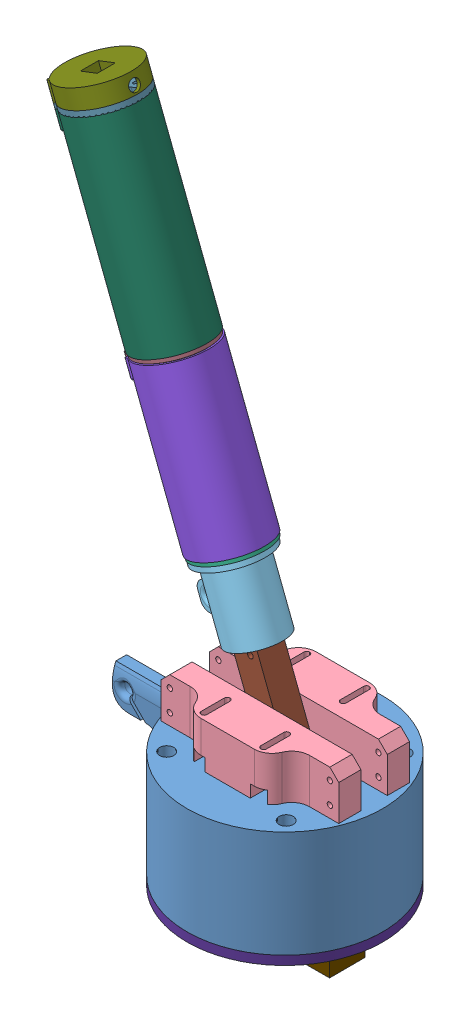
SolidWorks assembly twin_collective, configuration По умолчанию. Lengths in mm.
Overall size (179.32 375.53 110.36).
20 component instances, 18 part files, 53 mates.
Components (placement in the parent):
- twin_collective_enclosure_twin_collective01-1: twin_collective_enclosure_twin_collective01 [По умолчанию] at origin size (147.09 60.09 110)
- twin_collective_lever_frame_twin_collective04-1: twin_collective_lever_frame_twin_collective04 [По умолчанию] at (25.25 42 0) x (0 0 1) z (0 -1 0) size (56 48 30)
- 608_bearing_v1-1: 608_bearing_v1 [По умолчанию] at (9.25 42 10.5) x (1 0 0) z (0 -1 0) size (22 7.15 22)
- 608_bearing_v1-2: 608_bearing_v1 [По умолчанию] at (9.25 42 -10.5) x (1 0 0) z (0 1 0) size (22 7.15 22)
- twin_collective_tensioner_twin_collective06-3: twin_collective_tensioner_twin_collective06 [По умолчанию] at (-0.1 60 19.6) x (0 0 -1) z (1 0 0) size (25 25 100)
- twin_collective_tensioner_twin_collective06-4: twin_collective_tensioner_twin_collective06 [По умолчанию] at (-0.1 60 -20.2) x (0 0 1) z (-1 0 0) size (25 25 100)
- twin_collective_rubber_bands_holder_twin_collective08-1: twin_collective_rubber_bands_holder_twin_collective08 [По умолчанию] at (-16.0057 107.3923 -0.675) x (0 0 -1) z (0.932972 0.359949 0) size (38 40 44.15)
- twin_collective_throttle2_frame_p1_twin_collective09-1: twin_collective_throttle2_frame_p1_twin_collective09 [По умолчанию] at (-46.9714 188.6959 -0.65) x (0.932972 0.359949 0) z (0 0 -1) size (39 77 39)
- twin_collective_throttle2_frame_p2_twin_collective10-1: twin_collective_throttle2_frame_p2_twin_collective10 [По умолчанию] at (-52.3707 202.6905 -0.65) x (-0.932972 -0.359949 0) z (0 0 -1) size (36 27 34)
- twin_collective_throttle2_grip_twin_collective11-1: twin_collective_throttle2_grip_twin_collective11 [По умолчанию] at (-30.7737 146.7121 -0.65) x (-0.92274 -0.356001 -0.147697) z (-0.359949 0.932972 0) size (40 40 86.4)
- alu_square_pipe_10x10x130-1: alu_square_pipe_10x10x130 [По умолчанию] at (8.6574 44.0222 -0.475) x (-0.932972 -0.359949 0) z (0 0 -1) size (9.9 130 9.9)
- alu_square_pipe_10x10x50-1: alu_square_pipe_10x10x50 [По умолчанию] at (-56.6901 213.8861 -0.475) x (0.932972 0.359949 0) z (0 0 1) size (9.9 50 9.9)
- twin_collective_lever_connector_twin_collective05-1: twin_collective_lever_connector_twin_collective05 [По умолчанию] at (-2.6643 72.8814 -7.7) x (0 0 1) z (0.359949 -0.932972 0) size (42.8 14.8 74)
- twin_collective_magnet_holder_6x6x4mm_twin_collective07-1: twin_collective_magnet_holder_6x6x4mm_twin_collective07 [По умолчанию] at (9.25 42 -20.7) x (0.999763 0.021783 0) z (-0.021783 0.999763 0) size (8.6 12 13.8)
- twin_collective_throttle1_frame_p1_twin_collective12-1: twin_collective_throttle1_frame_p1_twin_collective12 [По умолчанию] at (-82.4431 281.1231 -0.3) x (0.932972 0.359949 0) z (0 0 -1) size (39 92 39)
- twin_collective_throttle1_frame_p2_twin_collective13-2: twin_collective_throttle1_frame_p2_twin_collective13 [По умолчанию] at (-87.8423 295.1177 -0.3) x (-0.932972 -0.359949 0) z (0 0 -1) size (40 39 40)
- twin_collective_throttle1_grip_twin_collective14-1: twin_collective_throttle1_grip_twin_collective14 [По умолчанию] at (-62.6459 229.8096 -0.3) x (-0.919515 -0.354757 -0.16923) z (-0.359949 0.932972 0) size (40 40 106.4)
- twin_collective_head_i2c_connector_housing_twin_collective15-1: twin_collective_head_i2c_connector_housing_twin_collective15 [По умолчанию] at (-101.8803 331.5036 -0.3) x (0 0 -1) z (0.932972 0.359949 0) size (40 10 40)
- twin_collective_enclosure_bottom_p1_twin_collective02-1: twin_collective_enclosure_bottom_p1_twin_collective02 [По умолчанию] at (0.0001 -5 0.0001) x (-0.999995 0 0.0033) z (-0.0033 0 -0.999995) size (110 22.5 110)
- twin_collective_enclosure_bottom_p2_twin_collective03-1: twin_collective_enclosure_bottom_p2_twin_collective03 [По умолчанию] at (0.0001 -17.5 0.0001) x (0.0033 0 0.999995) z (0.999995 0 -0.0033) size (30 10 70)
Mates (geometry in assembly coordinates):
- Концентричный2: concentric aligned: cylinder of twin_collective_enclosure_twin_collective01-1 through (-16.75 0 -20.5) axis (0 1 0) radius 1.5; cylinder of twin_collective_lever_frame_twin_collective04-1 through (-16.75 27 -20.5) axis (0 1 0) radius 1.5
- Концентричный4: concentric aligned: cylinder of twin_collective_enclosure_twin_collective01-1 through (-16.75 0 20.5) axis (0 1 0) radius 1.5; cylinder of twin_collective_lever_frame_twin_collective04-1 through (-16.75 27 20.5) axis (0 1 0) radius 1.5
- Совпадение1: coincident anti-aligned: plane of twin_collective_enclosure_twin_collective01-1 through (22.5 57 22.5) normal (0 -1 0); plane of twin_collective_lever_frame_twin_collective04-1 through (-16.75 57 17.5) normal (0 1 0)
- Концентричный5: concentric anti-aligned: cylinder of twin_collective_lever_frame_twin_collective04-1 through (9.25 42 -10.5) axis (0 0 -1) radius 11.1; cylinder of 608_bearing_v1-2 through (9.25 42 -13.975) axis (0 0 1) radius 11
- Совпадение2: coincident anti-aligned: plane of twin_collective_lever_frame_twin_collective04-1 through (9.25 42 -10.5) normal (0 0 -1); plane of 608_bearing_v1-2 through (9.25 42 -10.5) normal (0 0 1)
- Концентричный6: concentric anti-aligned: cylinder of twin_collective_lever_frame_twin_collective04-1 through (9.25 42 10.5) axis (0 0 1) radius 11.1; cylinder of 608_bearing_v1-1 through (9.25 42 13.975) axis (0 0 -1) radius 11
- Совпадение3: coincident anti-aligned: plane of twin_collective_lever_frame_twin_collective04-1 through (9.25 42 10.5) normal (0 0 1); plane of 608_bearing_v1-1 through (9.25 42 10.5) normal (0 0 -1)
- Совпадение19: coincident anti-aligned: plane of twin_collective_enclosure_twin_collective01-1 through (0 60 0) normal (0 1 0); plane of twin_collective_tensioner_twin_collective06-4 through (-0.1 60 -20.2) normal (0 -1 0)
- Совпадение20: coincident anti-aligned: plane of twin_collective_enclosure_twin_collective01-1 through (0 60 0) normal (0 1 0); plane of twin_collective_tensioner_twin_collective06-3 through (-0.1 60 19.6) normal (0 -1 0)
- Coincident58: coincident anti-aligned: plane of twin_collective_throttle2_frame_p1_twin_collective09-1 through (-30.7737 146.7121 -0.65) normal (-0.359949 0.932972 0); plane of twin_collective_throttle2_grip_twin_collective11-1 through (-30.7737 146.7121 -0.65) normal (0.359949 -0.932972 0)
- Concentric15: concentric aligned: cylinder of twin_collective_throttle2_frame_p2_twin_collective10-1 through (-62.0893 227.8807 -0.65) axis (0.359949 -0.932972 0) radius 18; cylinder of twin_collective_throttle2_grip_twin_collective11-1 through (-61.8733 227.3209 -0.65) axis (0.359949 -0.932972 0) radius 18.5
- Coincident87: coincident anti-aligned: plane of twin_collective_throttle2_frame_p1_twin_collective09-1 through (-49.2333 180.3203 -5.775) normal (0.932972 0.359949 0); plane of alu_square_pipe_10x10x130-1 through (-42.7542 163.5268 -5.425) normal (-0.932972 -0.359949 0)
- Coincident88: coincident anti-aligned: plane of twin_collective_throttle2_frame_p1_twin_collective09-1 through (-49.2333 180.3203 4.475) normal (0 0 -1); plane of alu_square_pipe_10x10x130-1 through (-42.7542 163.5268 4.475) normal (0 0 1)
- Coincident90: coincident aligned: plane of twin_collective_throttle2_frame_p1_twin_collective09-1 through (-37.9727 165.3716 -0.65) normal (-0.359949 0.932972 0); plane of alu_square_pipe_10x10x130-1 through (-38.136 165.3086 -0.475) normal (-0.359949 0.932972 0)
- Coincident91: coincident anti-aligned: plane of twin_collective_rubber_bands_holder_twin_collective08-1 through (-25.5989 146.565 4.475) normal (0 0 -1); plane of alu_square_pipe_10x10x130-1 through (-42.7542 163.5268 4.475) normal (0 0 1)
- Coincident92: coincident anti-aligned: plane of twin_collective_rubber_bands_holder_twin_collective08-1 through (-25.5989 146.565 -5.825) normal (-0.932972 -0.359949 0); plane of alu_square_pipe_10x10x130-1 through (-33.5178 167.0903 -5.425) normal (0.932972 0.359949 0)
- Concentric21: concentric anti-aligned: cylinder of twin_collective_throttle2_frame_p1_twin_collective09-1 through (-30.7737 146.7121 -0.65) axis (-0.359949 0.932972 0) radius 18; cylinder of twin_collective_throttle2_grip_twin_collective11-1 through (-61.8733 227.3209 -0.65) axis (0.359949 -0.932972 0) radius 18.5
- Parallel10: parallel anti-aligned: plane of twin_collective_throttle2_frame_p1_twin_collective09-1 through (-43.3286 222.2566 -4.2771) normal (0.932972 0.359949 0); plane of twin_collective_throttle2_frame_p2_twin_collective10-1 through (-43.1632 222.7492 4.8979) normal (-0.932972 -0.359949 0)
- Coincident119: coincident anti-aligned: plane of twin_collective_throttle2_frame_p1_twin_collective09-1 through (-52.3707 202.6905 -0.65) normal (-0.359949 0.932972 0); plane of twin_collective_throttle2_frame_p2_twin_collective10-1 through (-52.3707 202.6905 -0.65) normal (0.359949 -0.932972 0)
- Coincident120: coincident anti-aligned: circle of twin_collective_throttle2_frame_p2_twin_collective10-1; cylinder of alu_square_pipe_10x10x50-1 through (-58.4898 218.551 4.475) axis (0 0 -1) radius 1.5
- Coincident125: coincident anti-aligned: plane of twin_collective_throttle2_frame_p2_twin_collective10-1 through (-66.8708 226.036 4.475) normal (0 0 -1); plane of alu_square_pipe_10x10x50-1 through (-70.0693 262.3165 4.475) normal (0 0 1)
- Coincident126: coincident anti-aligned: plane of twin_collective_rubber_bands_holder_twin_collective08-1 through (-30.4037 144.7112 -0.675) normal (-0.359949 0.932972 0); plane of twin_collective_throttle2_frame_p1_twin_collective09-1 through (-30.0538 144.8462 -0.65) normal (0.359949 -0.932972 0)
- Concentric25: concentric aligned: cylinder of 608_bearing_v1-2 through (9.25 42 -13.975) axis (0 0 1) radius 4; cylinder of twin_collective_lever_connector_twin_collective05-1 through (9.25 42 -20.7) axis (0 0 1) radius 3.9
- Coincident127: coincident anti-aligned: plane of twin_collective_lever_frame_twin_collective04-1 through (16.75 27 -7.7) normal (0 0 1); plane of twin_collective_lever_connector_twin_collective05-1 through (-2.6643 72.8814 -7.7) normal (0 0 -1)
- Coincident128: coincident anti-aligned: plane of alu_square_pipe_10x10x130-1 through (-42.7542 163.5268 -5.425) normal (0 0 -1); plane of twin_collective_lever_connector_twin_collective05-1 through (12.1957 48.6029 -5.425) normal (0 0 1)
- Coincident129: coincident anti-aligned: plane of alu_square_pipe_10x10x130-1 through (-33.5178 167.0903 -5.425) normal (0.932972 0.359949 0); plane of twin_collective_lever_connector_twin_collective05-1 through (12.1957 48.6029 -5.425) normal (-0.932972 -0.359949 0)
- Coincident130: coincident anti-aligned: plane of twin_collective_rubber_bands_holder_twin_collective08-1 through (-16.0057 107.3923 -0.675) normal (0.359949 -0.932972 0); plane of twin_collective_lever_connector_twin_collective05-1 through (-9.0784 110.065 7.1) normal (-0.359949 0.932972 0)
- Concentric26: concentric aligned: cylinder of twin_collective_lever_connector_twin_collective05-1 through (9.25 42 -20.7) axis (0 0 1) radius 1.5; cylinder of twin_collective_magnet_holder_6x6x4mm_twin_collective07-1 through (9.25 42 -32.7) axis (0 0 1) radius 1.6
- Coincident131: coincident anti-aligned: plane of twin_collective_lever_connector_twin_collective05-1 through (9.25 42 -20.7) normal (0 0 -1); plane of twin_collective_magnet_holder_6x6x4mm_twin_collective07-1 through (9.25 42 -20.7) normal (0 0 1)
- Lock1: lock: unknown of twin_collective_lever_connector_twin_collective05-1; unknown of twin_collective_magnet_holder_6x6x4mm_twin_collective07-1
- Tangent1: tangent anti-aligned: cylinder of twin_collective_enclosure_twin_collective01-1 through (-16.75 0 -20.5) axis (0 1 0) radius 1.5; plane of twin_collective_tensioner_twin_collective06-4 through (-15.25 85 -14.7) normal (-1 0 0)
- Tangent2: tangent anti-aligned: cylinder of twin_collective_enclosure_twin_collective01-1 through (16.75 0 -20.5) axis (0 1 0) radius 1.5; plane of twin_collective_tensioner_twin_collective06-4 through (18.25 85 -14.6523) normal (-1 0 0)
- Tangent3: tangent anti-aligned: cylinder of twin_collective_enclosure_twin_collective01-1 through (16.75 0 20.5) axis (0 1 0) radius 1.5; plane of twin_collective_tensioner_twin_collective06-3 through (18.25 85 14.1) normal (-1 0 0)
- Tangent4: tangent anti-aligned: cylinder of twin_collective_enclosure_twin_collective01-1 through (-16.75 0 20.5) axis (0 1 0) radius 1.5; plane of twin_collective_tensioner_twin_collective06-3 through (-15.25 85 14.0523) normal (-1 0 0)
- Coincident133: coincident anti-aligned: plane of twin_collective_tensioner_twin_collective06-3 through (49.9 85 7.1) normal (0 0 -1); plane of twin_collective_lever_connector_twin_collective05-1 through (-2.6643 72.8814 7.1) normal (0 0 1)
- Coincident134: coincident anti-aligned: plane of twin_collective_tensioner_twin_collective06-4 through (-50.1 85 -7.7) normal (0 0 1); plane of twin_collective_lever_connector_twin_collective05-1 through (-2.6643 72.8814 -7.7) normal (0 0 -1)
- Coincident135: coincident anti-aligned: plane of alu_square_pipe_10x10x50-1 through (-70.0693 262.3165 -5.425) normal (0 0 -1); plane of twin_collective_throttle1_frame_p1_twin_collective12-1 through (-81.1055 263.4178 -5.425) normal (0 0 1)
- Coincident136: coincident anti-aligned: plane of alu_square_pipe_10x10x50-1 through (-79.3057 258.753 4.475) normal (-0.932972 -0.359949 0); plane of twin_collective_throttle1_frame_p1_twin_collective12-1 through (-81.1055 263.4178 -5.425) normal (0.932972 0.359949 0)
- Coincident137: coincident anti-aligned: plane of twin_collective_throttle2_frame_p2_twin_collective10-1 through (-62.0893 227.8807 -0.65) normal (-0.359949 0.932972 0); plane of twin_collective_throttle1_frame_p1_twin_collective12-1 through (-61.926 227.9437 -0.3) normal (0.359949 -0.932972 0)
- Concentric29: concentric anti-aligned: cylinder of twin_collective_throttle1_frame_p1_twin_collective12-1 through (-62.6459 229.8096 -0.3) axis (-0.359949 0.932972 0) radius 18; cylinder of twin_collective_throttle1_frame_p2_twin_collective13-2 through (-100.8005 328.7047 -0.3) axis (0.359949 -0.932972 0) radius 18
- Parallel12: parallel anti-aligned: plane of twin_collective_throttle1_frame_p1_twin_collective12-1 through (-80.6 319.3487 -3.9271) normal (0 0 -1); plane of twin_collective_throttle1_frame_p2_twin_collective13-2 through (-80.4346 319.8413 -4.1021) normal (0 0 1)
- Coincident142: coincident anti-aligned: plane of twin_collective_throttle1_frame_p1_twin_collective12-1 through (-87.8423 295.1177 -0.3) normal (-0.359949 0.932972 0); plane of twin_collective_throttle1_frame_p2_twin_collective13-2 through (-87.8423 295.1177 -0.3) normal (0.359949 -0.932972 0)
- Concentric30: concentric aligned: cylinder of twin_collective_throttle1_frame_p2_twin_collective13-2 through (-100.8005 328.7047 -0.3) axis (0.359949 -0.932972 0) radius 18; cylinder of twin_collective_throttle1_grip_twin_collective14-1 through (-100.9445 329.0779 -0.3) axis (0.359949 -0.932972 0) radius 18.5
- Coincident143: coincident anti-aligned: plane of twin_collective_throttle1_frame_p1_twin_collective12-1 through (-62.6459 229.8096 -0.3) normal (-0.359949 0.932972 0); plane of twin_collective_throttle1_grip_twin_collective14-1 through (-62.6459 229.8096 -0.3) normal (0.359949 -0.932972 0)
- Concentric31: concentric aligned: cylinder of twin_collective_throttle1_frame_p2_twin_collective13-2 through (-100.8005 328.7047 -0.3) axis (0.359949 -0.932972 0) radius 18; cylinder of twin_collective_head_i2c_connector_housing_twin_collective15-1 through (-105.4798 340.8333 -0.3) axis (0.359949 -0.932972 0) radius 20
- Parallel13: parallel aligned: plane of twin_collective_throttle1_frame_p2_twin_collective13-2 through (-96.019 330.5494 -5.425) normal (-0.932972 -0.359949 0); plane of twin_collective_head_i2c_connector_housing_twin_collective15-1 through (-100.7217 342.6691 -5.4) normal (-0.932972 -0.359949 0)
- Concentric32: concentric aligned: cylinder of twin_collective_enclosure_twin_collective01-1 through (0 50 0) axis (0 -1 0) radius 50; cylinder of twin_collective_enclosure_bottom_p1_twin_collective02-1 through (0.0001 5 0.0001) axis (0 -1 0) radius 49.9
- Coincident146: coincident anti-aligned: plane of twin_collective_enclosure_twin_collective01-1 through (0 0 0) normal (0 -1 0); plane of twin_collective_enclosure_bottom_p1_twin_collective02-1 through (0.0001 0 0.0001) normal (0 1 0)
- Coincident147: coincident anti-aligned: plane of twin_collective_enclosure_bottom_p1_twin_collective02-1 through (0.0001 -17.5 0.0001) normal (0 -1 0); plane of twin_collective_enclosure_bottom_p2_twin_collective03-1 through (0.0001 -17.5 0.0001) normal (0 1 0)
- Concentric34: concentric anti-aligned: cylinder of twin_collective_enclosure_bottom_p1_twin_collective02-1 through (25 5 -0.0824) axis (0 -1 0) radius 4.15; cylinder of twin_collective_enclosure_bottom_p2_twin_collective03-1 through (25 -27.5 -0.0824) axis (0 1 0) radius 4.15
- Concentric35: concentric anti-aligned: cylinder of twin_collective_enclosure_bottom_p1_twin_collective02-1 through (-24.9997 5 0.0826) axis (0 -1 0) radius 4.15; cylinder of twin_collective_enclosure_bottom_p2_twin_collective03-1 through (-24.9997 -27.5 0.0826) axis (0 1 0) radius 4.15
- Concentric36: concentric anti-aligned: cylinder of twin_collective_enclosure_twin_collective01-1 through (-33.5917 0 -32.8724) axis (0 1 0) radius 4; cylinder of twin_collective_enclosure_bottom_p1_twin_collective02-1 through (-33.5917 5 -32.8724) axis (0 -1 0) radius 4.1
- Coincident148: coincident anti-aligned: plane of twin_collective_throttle1_frame_p2_twin_collective13-2 through (-101.8803 331.5036 -0.3) normal (-0.359949 0.932972 0); plane of twin_collective_head_i2c_connector_housing_twin_collective15-1 through (-101.8803 331.5036 -0.3) normal (0.359949 -0.932972 0)
